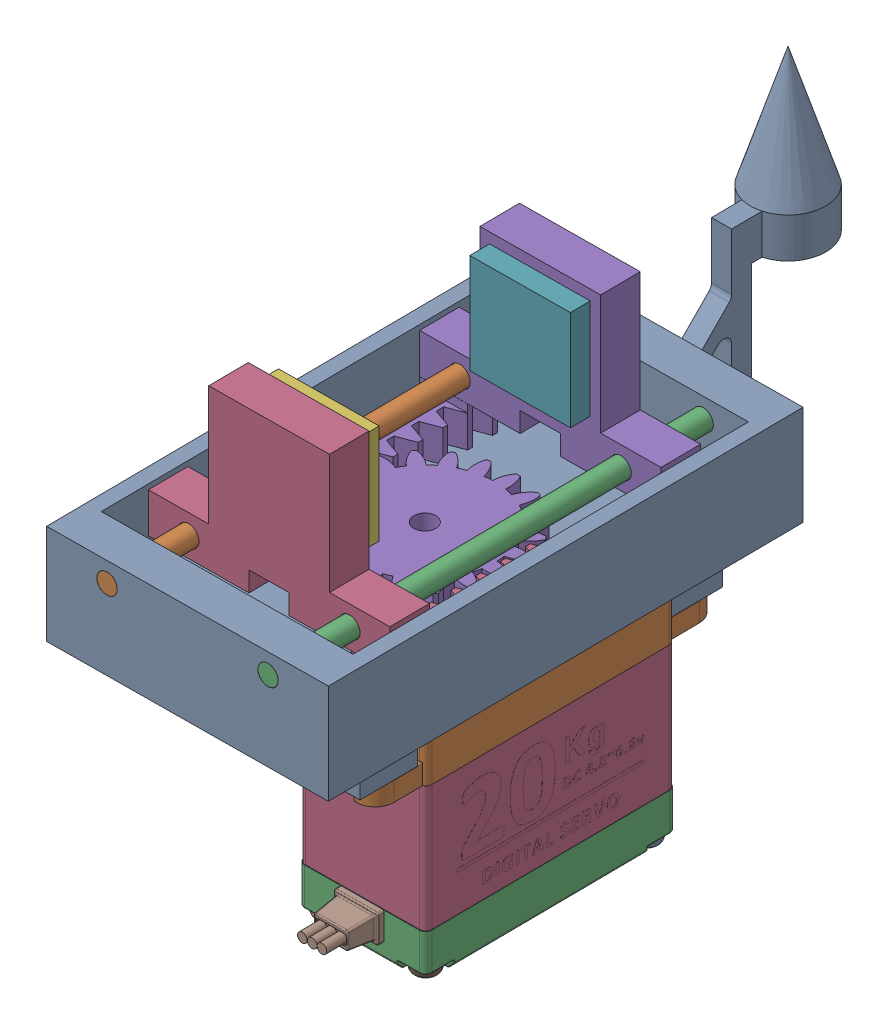
SolidWorks assembly Full Gripper, configuration Default. Lengths in mm.
Overall size (45.34 90.42 102.78).
9 component instances, 6 part files, 24 mates.
Components (placement in the parent):
- RackPinion_casing-1: RackPinion_casing [Default] at (-20.5257 -68.4592 59.5142) x (-0.008727 0 -0.999962) z (0.999962 0 -0.008727) size (102.4 59.65 44.45)
- JawRod-1: JawRod [Default] at (-52.219 -55.7592 66.141) x (-0.616727 -0.787159 0.005382) z (-0.008727 0 -0.999962) size (3.17 3.17 76.2)
- JawRod-2: JawRod [Default] at (-26.82 -55.7592 65.9194) x (-0.616727 -0.787159 0.005382) z (-0.008727 0 -0.999962) size (3.17 3.17 76.2)
- RackGear-1: RackGear [Inch - Rack-spur - rectangular 20DP 20PA .25FW .25PH 2L---SAll] at (-20.5845 -58.9342 52.7704) x (-0.008727 0 -0.999962) z (0 1 0) size (31.75 38.1 31.75)
- spur gear-2: spur gear [Inch - Spur gear 20DP 20T 20PA .25FW ---S20N3.0H2.0L0.125N] at (-39.852 -65.2842 27.9317) x (0 1 0) z (-0.514586 0 0.857439) size (12.06 27.69 27.69)
- DS3218MG MS24 Digital Servo 270-1: DS3218MG MS24 Digital Servo 270 [Default] at (-39.852 -86.8592 27.9317) x (-0.999962 0 0.008727) z (-0.008727 0 -0.999962) size (20.1 45.99 55.6)
- RackGear-2: RackGear [Inch - Rack-spur - rectangular 20DP 20PA .25FW .25PH 2L---SAll] at (-59.1184 -58.9342 3.2176) x (0.008727 0 0.999962) z (0 1 0) size (31.75 38.1 31.75)
- FingerTip-1: FingerTip [Default] at (-47.5906 -51.0602 43.4808) x (0.999962 0 -0.008727) z (0 -1 0) size (15.88 6.35 15.88)
- FingerTip-2: FingerTip [Default] at (-48.0421 -51.0602 6.2961) x (0.999962 0 -0.008727) z (0 -1 0) size (15.88 6.35 15.88)
Mates (geometry in assembly coordinates):
- Concentric1: concentric aligned: cylinder of RackPinion_casing-1 through (-39.852 -68.4592 27.9317) axis (0 1 0) radius 5.25; cylinder of spur gear-2 through (-39.852 -72.2692 27.9317) axis (0 1 0) radius 5
- Coincident1: coincident anti-aligned: plane of RackPinion_casing-1 through (-20.5257 -65.2842 59.5142) normal (0 1 0); plane of spur gear-2 through (-39.852 -65.2842 27.9317) normal (0 -1 0)
- Concentric2: concentric anti-aligned: cylinder of spur gear-2 through (-39.852 -14.4841 27.9317) axis (0 -1 0) radius 1.75; cylinder of DS3218MG MS24 Digital Servo 270-1 through (-39.852 -72.4592 27.9317) axis (0 1 0) radius 1.25
- Coincident2: coincident anti-aligned: plane of RackPinion_casing-1 through (-20.5257 -83.6592 59.5142) normal (0 -1 0); plane of DS3218MG MS24 Digital Servo 270-1 through (-39.852 -83.6592 27.9317) normal (0 1 0)
- Concentric3: concentric anti-aligned: cylinder of RackPinion_casing-1 through (-50.4609 -76.0592 6.0211) axis (-0.999962 0 0.008727) radius 1.75; cylinder of Wrist-1 through (-59.6529 -76.0592 6.1013) axis (0.999962 0 -0.008727) radius 1.5
- Concentric4: concentric anti-aligned: cylinder of RackPinion_casing-1 through (-50.234 -76.0592 32.0201) axis (-0.999962 0 0.008727) radius 1.75; cylinder of Wrist-1 through (-59.426 -76.0592 32.1003) axis (0.999962 0 -0.008727) radius 1.5
- Coincident3: coincident anti-aligned: plane of RackPinion_casing-1 through (-55.0874 -143.2242 43.0806) normal (0.999962 0 -0.008727); plane of Wrist-1 through (-55.297 -148.4592 19.0638) normal (-0.999962 0 0.008727)
- Concentric5: concentric anti-aligned: cylinder of RackPinion_casing-1 through (-52.219 -55.7592 66.141) axis (-0.008727 0 -0.999962) radius 1.6; cylinder of JawRod-1 through (-52.884 -55.7592 -10.0561) axis (0.008727 0 0.999962) radius 1.5875
- Coincident4: coincident aligned: plane of RackPinion_casing-1 through (-59.2338 -52.5842 -10.0006) normal (-0.008727 0 -0.999962); plane of JawRod-1 through (-52.884 -55.7592 -10.0561) normal (-0.008727 0 -0.999962)
- Concentric6: concentric anti-aligned: cylinder of RackPinion_casing-1 through (-26.82 -55.7592 65.9194) axis (-0.008727 0 -0.999962) radius 1.6; cylinder of JawRod-2 through (-27.485 -55.7592 -10.2777) axis (0.008727 0 0.999962) radius 1.5875
- Coincident5: coincident aligned: plane of RackPinion_casing-1 through (-59.2338 -52.5842 -10.0006) normal (-0.008727 0 -0.999962); plane of JawRod-2 through (-27.485 -55.7592 -10.2777) normal (-0.008727 0 -0.999962)
- Concentric7: concentric aligned: cylinder of JawRod-2 through (-27.485 -55.7592 -10.2777) axis (0.008727 0 0.999962) radius 1.5875; cylinder of RackGear-1 through (-27.0304 -55.7592 41.8094) axis (0.008727 0 0.999962) radius 1.65
- Concentric8: concentric anti-aligned: cylinder of JawRod-1 through (-52.884 -55.7592 -10.0561) axis (0.008727 0 0.999962) radius 1.5875; cylinder of RackGear-1 through (-52.2926 -55.7592 57.7142) axis (-0.008727 0 -0.999962) radius 1.65
- Concentric9: concentric anti-aligned: cylinder of JawRod-1 through (-52.884 -55.7592 -10.0561) axis (0.008727 0 0.999962) radius 1.5875; cylinder of RackGear-2 through (-52.6725 -55.7592 14.1787) axis (-0.008727 0 -0.999962) radius 1.65
- Concentric10: concentric aligned: cylinder of JawRod-2 through (-27.485 -55.7592 -10.2777) axis (0.008727 0 0.999962) radius 1.5875; cylinder of RackGear-2 through (-27.4103 -55.7592 -1.7262) axis (0.008727 0 0.999962) radius 1.65
- Parallel2: parallel aligned: plane of RackPinion_casing-1 through (-30.5883 -83.6592 -2.0549) normal (0.999962 0 -0.008727); plane of DS3218MG MS24 Digital Servo 270-1 through (-30.2996 -83.6592 45.349) normal (0.999962 0 -0.008727)
- Coincident6: coincident anti-aligned: plane of RackGear-1 through (-20.6122 -58.9342 49.5956) normal (-0.008727 0 -0.999962); plane of FingerTip-1 through (-47.5352 -51.0602 49.8305) normal (0.008727 0 0.999962)
- Coincident7: coincident anti-aligned: plane of RackGear-1 through (-47.5352 -35.1852 49.8305) normal (0 -1 0); plane of FingerTip-1 through (-47.5352 -35.1852 49.8305) normal (0 1 0)
- Coincident8: coincident anti-aligned: plane of RackGear-1 through (-47.5352 -35.1852 49.8305) normal (0.999962 0 -0.008727); plane of FingerTip-1 through (-47.5352 -51.0602 49.8305) normal (-0.999962 0 0.008727)
- Coincident10: coincident anti-aligned: plane of RackGear-2 through (-32.1677 -35.1852 6.1575) normal (-0.999962 0 0.008727); plane of FingerTip-2 through (-32.1123 -51.0602 12.5073) normal (0.999962 0 -0.008727)
- Coincident11: coincident anti-aligned: plane of RackGear-2 through (-32.1677 -35.1852 6.1575) normal (0 -1 0); plane of FingerTip-2 through (-47.9867 -35.1852 12.6458) normal (0 1 0)
- Coincident12: coincident anti-aligned: plane of RackGear-2 through (-59.0907 -58.9342 6.3925) normal (0.008727 0 0.999962); plane of FingerTip-2 through (-48.0421 -51.0602 6.2961) normal (-0.008727 0 -0.999962)
- RackPinionMate2: rack pinion = 25.4 mm: line of RackGear-2 through (-59.0628 -60.2042 9.5849) axis (0.008727 0 0.999962); circle of spur gear-2
- RackPinionMate3: rack pinion = 25.4 mm: line of RackGear-1 through (-20.6401 -60.2042 46.4031) axis (-0.008727 0 -0.999962); circle of spur gear-2
